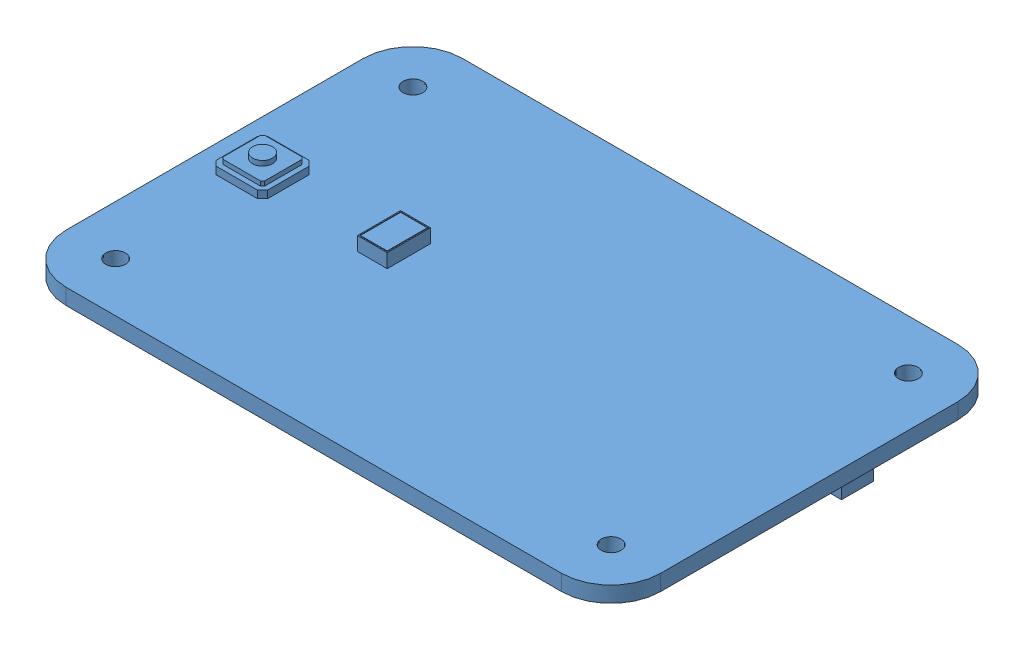
SolidWorks assembly Full_PCB_Assembly, configuration Default. Lengths in mm.
Overall size (61.7 6.61 40).
3 component instances, 3 part files, 7 mates.
Components (placement in the parent):
- PCB-1: PCB [Default] at (23.3501 34.2997 42.9781) size (60 5.3 40)
- USB_C_Female_Connector-1: USB_C_Female_Connector [Default] at (-4.6749 34.2997 42.9781) x (0 0 -1) z (0 -1 0) size (8.94 7.78 4.26)
- Reset Switch TS-1088-AR02016-XUNPU-1: Reset Switch TS-1088-AR02016-XUNPU [Default] at (16.3501 34.2997 25.4781) x (1 0 0) z (0 0 -1) size (4 2.5 3)
Mates (geometry in assembly coordinates):
- Distance2: distance = 0.15 mm anti-aligned: plane of PCB-1 through (23.3501 34.2997 42.9781) normal (0 -1 0); plane of USB_C_Female_Connector-1 through (-8.3499 34.1497 39.7881) normal (0 1 0)
- Width1: width anti-aligned: plane of PCB-1 through (-6.6499 35.8997 22.9781) normal (0 0 -1); plane of PCB-1 through (-6.6499 35.8997 62.9781) normal (0 0 1); plane of USB_C_Female_Connector-1 through (-8.3499 32.2697 47.4481) normal (0 0 1); plane of USB_C_Female_Connector-1 through (-8.3499 32.2697 38.5081) normal (0 0 -1)
- Distance1: distance = 1.7 mm aligned: plane of USB_C_Female_Connector-1 through (-8.3499 32.5697 40.5244) normal (-1 0 0); plane of PCB-1 through (-6.6499 35.8997 22.9781) normal (-1 0 0)
- Coincident3: coincident anti-aligned: plane of PCB-1 through (23.3501 34.2997 42.9781) normal (0 -1 0); plane of Reset Switch TS-1088-AR02016-XUNPU-1 through (16.3501 34.2997 25.4781) normal (0 1 0)
- Parallel3: parallel aligned: plane of PCB-1 through (-6.6499 35.8997 22.9781) normal (0 0 -1); plane of Reset Switch TS-1088-AR02016-XUNPU-1 through (14.3501 32.7997 23.9781) normal (0 0 -1)
- Distance3: distance = 1 mm aligned: plane of Reset Switch TS-1088-AR02016-XUNPU-1 through (14.3501 32.7997 23.9781) normal (0 0 -1); plane of PCB-1 through (-6.6499 35.8997 22.9781) normal (0 0 -1)
- Distance5: distance = 21 mm aligned: plane of Reset Switch TS-1088-AR02016-XUNPU-1 through (14.3501 32.7997 26.9781) normal (-1 0 0); plane of PCB-1 through (-6.6499 35.8997 22.9781) normal (-1 0 0)
